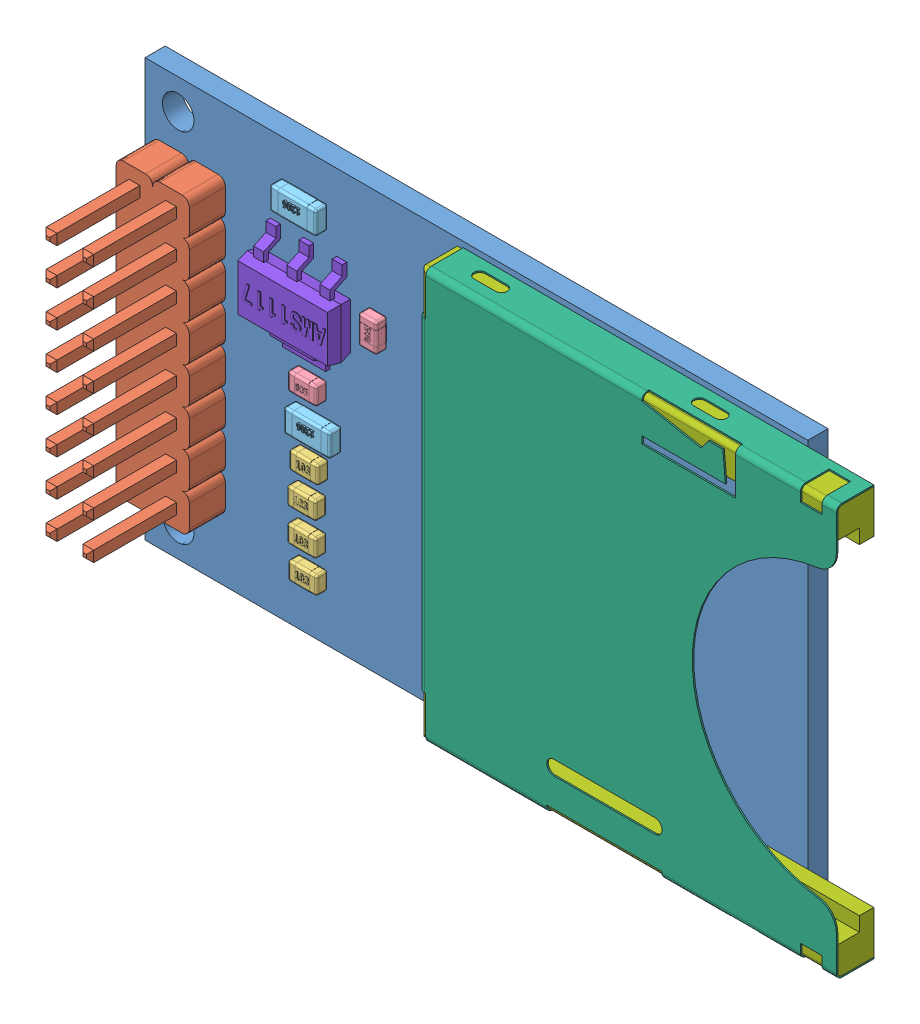
SolidWorks assembly SD_CARD, configuration По умолчанию. Lengths in mm.
Overall size (50.58 29 11.75).
24 component instances, 9 part files, 0 mates.
Components (placement in the parent):
- placa_Valor predeterminado-1: placa_Valor predeterminado [По умолчанию] at (3.95 1.25 46) size (46 29 1.4)
- 8pin_header-1: 8pin_header [По умолчанию] at (-17.2876 10.0086 47.4) x (1 0 0) z (0 -1 0) size (5.33 11.75 20.57)
- RESISTOR_SMD_103_Valor predeterminado-1: RESISTOR_SMD_103_Valor predeterminado [По умолчанию] at (-7.2773 -2.6338 47.41) x (-1 0 0) z (0 -1 0) size (2 0.82 1.27)
- RESISTOR_SMD_103_Valor predeterminado-2: RESISTOR_SMD_103_Valor predeterminado [По умолчанию] at (-7.4357 -4.8535 47.41) x (-1 0 0) z (0 -1 0) size (2 0.82 1.27)
- RESISTOR_SMD_103_Valor predeterminado-3: RESISTOR_SMD_103_Valor predeterminado [По умолчанию] at (-7.4239 -7.1062 47.41) x (-1 0 0) z (0 -1 0) size (2 0.82 1.27)
- RESISTOR_SMD_103_Valor predeterminado-4: RESISTOR_SMD_103_Valor predeterminado [По умолчанию] at (-7.3544 -9.3094 47.41) x (-1 0 0) z (0 -1 0) size (2 0.82 1.27)
- CAPACITOR_805_Valor predeterminado-1: CAPACITOR_805_Valor predeterminado [По умолчанию] at (-7.3836 2.0617 48.19) x (1 0 0) z (0 -1 0) size (2 0.81 1.27)
- CAPACITOR_805_Valor predeterminado-2: CAPACITOR_805_Valor predeterminado [По умолчанию] at (-2.84 7.627 48.19) x (0 1 0) z (1 0 0) size (2 0.81 1.27)
- CAPACITOR_1206_Valor predeterminado-1: CAPACITOR_1206_Valor predeterminado [По умолчанию] at (-8.5503 12.6947 47.41) x (1 0 0) z (0 1 0) size (3.2 0.97 1.62)
- CAPACITOR_1206_Valor predeterminado-2: CAPACITOR_1206_Valor predeterminado [По умолчанию] at (-7.5776 -0.189 47.41) x (1 0 0) z (0 1 0) size (3.2 0.97 1.62)
- SD_CASCA_Valor predeterminado-1: SD_CASCA_Valor predeterminado [По умолчанию] at (17.0291 1.1152 47.4) x (0 1 0) z (0 0 1) size (28.5 29 2.6)
- interno_sd_Valor predeterminado-1: interno_sd_Valor predeterminado [По умолчанию] at (2.6291 -13.0348 49.9) x (0 1 0) z (0 0 -1) size (28.3 28.9 2.5)
- AMS1117_Valor predeterminado-1: AMS1117_Valor predeterminado [По умолчанию] at (23.2923 6.9574 48.4051) x (-1 0 0) z (0 1 0) size (6.5 1.86 7)
- PINO_SD_Valor predeterminado-1: PINO_SD_Valor predeterminado [По умолчанию] at (0.4291 9.8987 47.525) x (0 -1 0) z (-1 0 0) size (0.8 1.05 2.3)
- PINO_SD_Valor predeterminado-2: PINO_SD_Valor predeterminado [По умолчанию] at (0.4291 5.0251 47.525) x (0 -1 0) z (-1 0 0) size (0.8 1.05 2.3)
- PINO_SD_Valor predeterminado-3: PINO_SD_Valor predeterminado [По умолчанию] at (0.4291 7.4702 47.525) x (0 -1 0) z (-1 0 0) size (0.8 1.05 2.3)
- PINO_SD_Valor predeterminado-4: PINO_SD_Valor predeterminado [По умолчанию] at (0.4291 3.5251 47.525) x (0 -1 0) z (-1 0 0) size (0.8 1.05 2.3)
- PINO_SD_Valor predeterminado-5: PINO_SD_Valor predeterminado [По умолчанию] at (0.4291 1.5842 47.525) x (0 -1 0) z (-1 0 0) size (0.8 1.05 2.3)
- PINO_SD_Valor predeterminado-6: PINO_SD_Valor predeterminado [По умолчанию] at (0.4291 -2.2975 47.525) x (0 -1 0) z (-1 0 0) size (0.8 1.05 2.3)
- PINO_SD_Valor predeterminado-7: PINO_SD_Valor predeterminado [По умолчанию] at (0.4291 0.0842 47.525) x (0 -1 0) z (-1 0 0) size (0.8 1.05 2.3)
- PINO_SD_Valor predeterminado-8: PINO_SD_Valor predeterminado [По умолчанию] at (0.4291 -7.1299 47.525) x (0 -1 0) z (-1 0 0) size (0.8 1.05 2.3)
- PINO_SD_Valor predeterminado-9: PINO_SD_Valor predeterminado [По умолчанию] at (0.4291 -4.7116 47.525) x (0 -1 0) z (-1 0 0) size (0.8 1.05 2.3)
- PINO_SD_Valor predeterminado-10: PINO_SD_Valor predeterminado [По умолчанию] at (0.4291 -11.8482 47.525) x (0 -1 0) z (-1 0 0) size (0.8 1.05 2.3)
- PINO_SD_Valor predeterminado-11: PINO_SD_Valor predeterminado [По умолчанию] at (0.4291 -8.6299 47.525) x (0 -1 0) z (-1 0 0) size (0.8 1.05 2.3)
